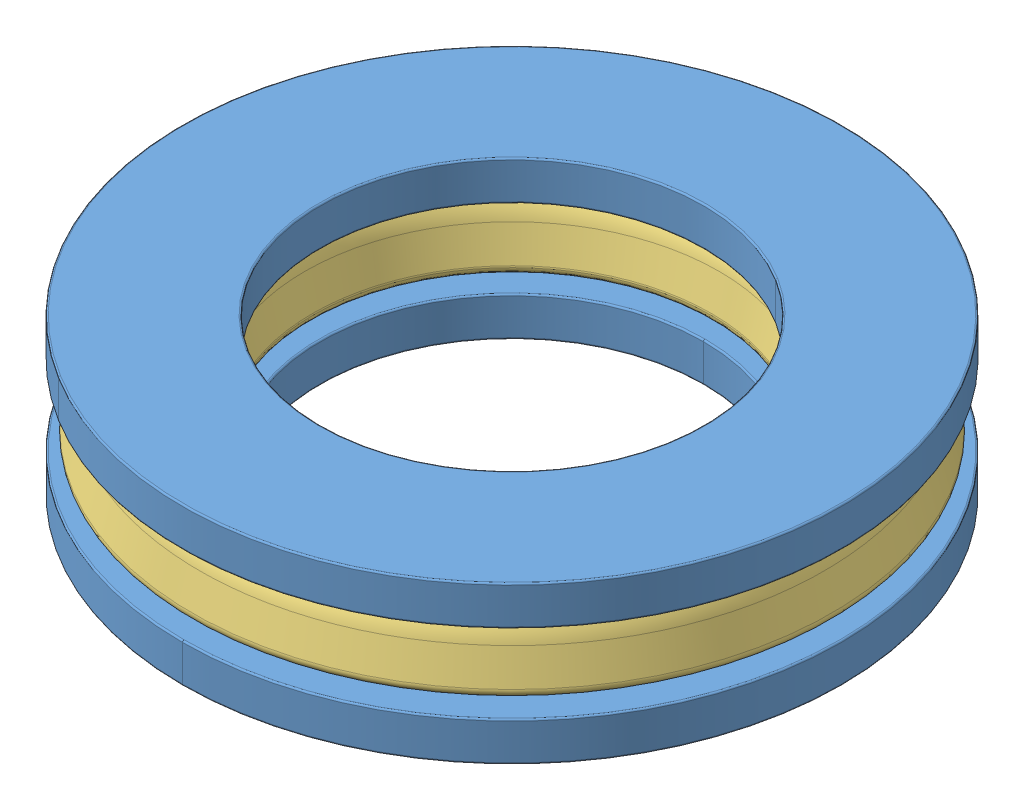
SolidWorks assembly Thrust_Bearing_12x21x5, configuration Default. Lengths in mm.
Overall size (28.91 5 28.91).
15 component instances, 3 part files, 0 mates.
Components (placement in the parent):
- 1613-0521-0012 assembly.STEP-1: 1613-0521-0012 assembly.STEP [Default] at origin size (28.91 5 28.91)
  - 1613-0521-0012 washer.STEP-1: 1613-0521-0012 washer.STEP [Default] at (4.541 9.4432 -9.2364) size (21 1.25 21)
  - 1613-0521-0012 washer.STEP-2: 1613-0521-0012 washer.STEP [Default] at (4.541 14.4432 -9.2364) x (-0.850562 0 -0.525875) z (-0.525875 0 0.850562) size (21 1.25 21)
  - 1613-0521-0012 ball.STEP-1: 1613-0521-0012 ball.STEP [Default] at (-0.0636 11.9432 -16.1059) x (0.890954 0.057695 0.450413) z (-0.453971 0.090183 0.886441) size (3 3 3)
  - 1613-0521-0012 ball.STEP-2: 1613-0521-0012 ball.STEP [Default] at (-3.0466 11.9432 -12.526) x (0.99303 0.057695 -0.102775) z (0.097342 0.090183 0.991157) size (3 3 3)
  - 1613-0521-0012 ball.STEP-3: 1613-0521-0012 ball.STEP [Default] at (-3.6206 11.9432 -7.9016) x (0.779826 0.057695 -0.623332) z (0.617749 0.090183 0.781187) size (3 3 3)
  - 1613-0521-0012 ball.STEP-4: 1613-0521-0012 ball.STEP [Default] at (-1.6033 11.9432 -3.701) x (0.319032 0.057695 -0.945986) z (0.942025 0.090183 0.323196) size (3 3 3)
  - 1613-0521-0012 ball.STEP-5: 1613-0521-0012 ball.STEP [Default] at (2.3647 11.9432 -1.2579) x (-0.243052 0.057695 -0.968296) z (0.967215 0.090183 -0.237407) size (3 3 3)
  - 1613-0521-0012 ball.STEP-6: 1613-0521-0012 ball.STEP [Default] at (7.0237 11.9432 -1.3479) x (-0.727969 0.057695 -0.683179) z (0.685321 0.090183 -0.722635) size (3 3 3)
  - 1613-0521-0012 ball.STEP-7: 1613-0521-0012 ball.STEP [Default] at (10.8945 11.9432 -3.9424) x (-0.98176 0.057695 -0.181157) z (0.185843 0.090183 -0.978432) size (3 3 3)
  - 1613-0521-0012 ball.STEP-8: 1613-0521-0012 ball.STEP [Default] at (12.748 11.9432 -8.2177) x (-0.92385 0.057695 0.378381) z (-0.37264 0.090183 -0.923584) size (3 3 3)
  - 1613-0521-0012 ball.STEP-9: 1613-0521-0012 ball.STEP [Default] at (11.9959 11.9432 -12.8165) x (-0.572624 0.057695 0.817785) z (-0.812811 0.090183 -0.575504) size (3 3 3)
  - 1613-0521-0012 ball.STEP-10: 1613-0521-0012 ball.STEP [Default] at (8.8769 11.9432 -16.2786) x (-0.039594 0.057695 0.997549) z (-0.994921 0.090183 -0.044706) size (3 3 3)
  - 1613-0521-0012 ball.STEP-11: 1613-0521-0012 ball.STEP [Default] at (4.3813 11.9432 -17.5049) x (0.506007 0.057695 0.860598) z (-0.861151 0.090183 0.500286) size (3 3 3)
  - 1613-0521-0012 carriage.STEP-1: 1613-0521-0012 carriage.STEP [Default] at (4.541 11.0282 -9.2364) x (0.704997 0 0.709211) z (-0.709211 0 0.704997) size (20.39 1.83 20.39)
